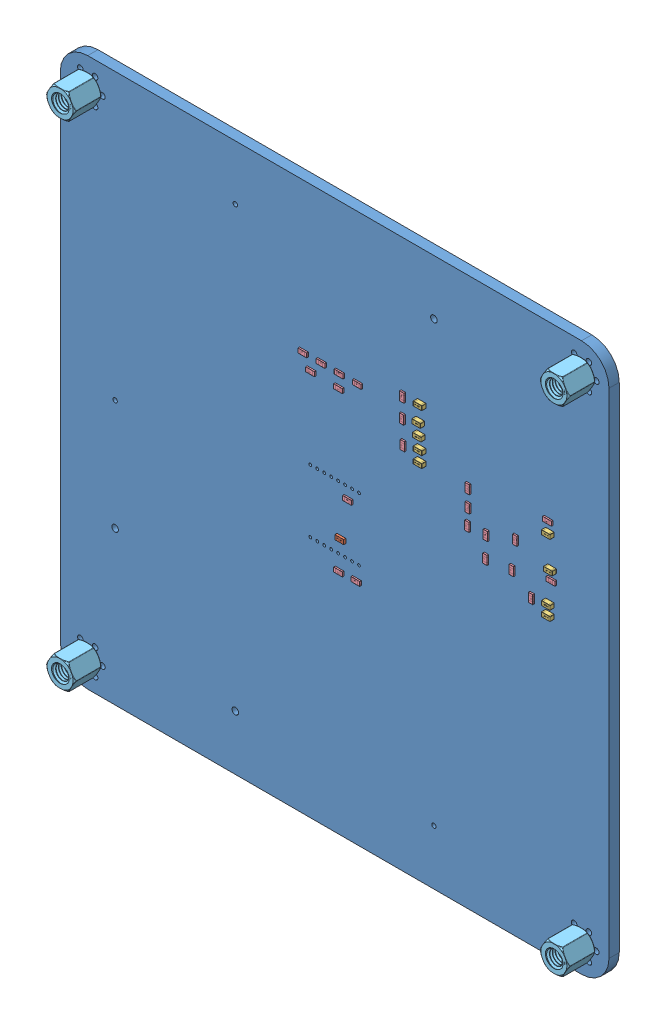
SolidWorks assembly sensor, configuration 默认. Lengths in mm.
Overall size (100 100 12.35).
156 component instances, 17 part files, 0 mates.
Components (placement in the parent):
- sensor_BOARD-1: sensor_BOARD [默认] at origin size (100 100 1.87)
- 0603R_RES-1-1: 0603R_RES-1 [默认] at (100.66 134.239 0.0102) x (-1 0 0) z (0 0 -1) size (1.6 0.82 0.45)
- 0603R_RES-1-2: 0603R_RES-1 [默认] at (75.184 135.128 0.0102) x (0 -1 0) z (0 0 -1) size (1.6 0.82 0.45)
- 0603R_RES-1-3: 0603R_RES-1 [默认] at (96.901 134.239 0.0102) x (-1 0 0) z (0 0 -1) size (1.6 0.82 0.45)
- 0603R_RES-1-4: 0603R_RES-1 [默认] at (77.089 133.528 0.0102) x (0 1 0) z (0 0 -1) size (1.6 0.82 0.45)
- 0603R_RES-1-5: 0603R_RES-1 [默认] at (74.803 117.551 0.0102) x (0 -1 0) z (0 0 -1) size (1.6 0.82 0.45)
- 0603R_RES-1-6: 0603R_RES-1 [默认] at (96.52 116.84 0.0102) x (-1 0 0) z (0 0 -1) size (1.6 0.82 0.45)
- 0603R_RES-1-7: 0603R_RES-1 [默认] at (77.089 115.951 0.0102) x (0 1 0) z (0 0 -1) size (1.6 0.82 0.45)
- 0603R_RES-1-8: 0603R_RES-1 [默认] at (100.914 98.044 0.0102) x (-1 0 0) z (0 0 -1) size (1.6 0.82 0.45)
- 0603R_RES-1-9: 0603R_RES-1 [默认] at (74.549 126.314 0.0102) x (0 -1 0) z (0 0 -1) size (1.6 0.82 0.45)
- 0603R_RES-1-10: 0603R_RES-1 [默认] at (96.723 126.365 0.0102) x (-1 0 0) z (0 0 -1) size (1.6 0.82 0.45)
- 0603R_RES-1-11: 0603R_RES-1 [默认] at (76.835 124.841 0.0102) x (0 1 0) z (0 0 -1) size (1.6 0.82 0.45)
- 0603R_RES-1-12: 0603R_RES-1 [默认] at (108.407 105.283 0.0102) x (-1 0 0) z (0 0 -1) size (1.6 0.82 0.45)
- 0603R_RES-1-13: 0603R_RES-1 [默认] at (108.331 103.251 0.0102) x (-1 0 0) z (0 0 -1) size (1.6 0.82 0.45)
- 0603R_RES-1-14: 0603R_RES-1 [默认] at (108.204 101.092 0.0102) x (-1 0 0) z (0 0 -1) size (1.6 0.82 0.45)
- 0603R_RES-1-15: 0603R_RES-1 [默认] at (108.204 98.679 0.0102) x (-1 0 0) z (0 0 -1) size (1.6 0.82 0.45)
- 0603R_RES-1-16: 0603R_RES-1 [默认] at (100.584 126.365 0.0102) x (-1 0 0) z (0 0 -1) size (1.6 0.82 0.45)
- 0603R_RES-1-17: 0603R_RES-1 [默认] at (120.777 104.14 1.8635) x (-1 0 0) z (0 0 1) size (1.6 0.82 0.45)
- 0603R_RES-1-18: 0603R_RES-1 [默认] at (156.159 113.284 0.0102) x (-1 0 0) z (0 0 -1) size (1.6 0.82 0.45)
- 0603R_RES-1-19: 0603R_RES-1 [默认] at (147.32 139.014 0.0102) x (0 -1 0) z (0 0 -1) size (1.6 0.82 0.45)
- 0603R_RES-1-20: 0603R_RES-1 [默认] at (145.161 139.014 0.0102) x (0 -1 0) z (0 0 -1) size (1.6 0.82 0.45)
- 0603R_RES-1-21: 0603R_RES-1 [默认] at (141.097 139.014 0.0102) x (0 -1 0) z (0 0 -1) size (1.6 0.82 0.45)
- 0603R_RES-1-22: 0603R_RES-1 [默认] at (143.129 139.014 0.0102) x (0 -1 0) z (0 0 -1) size (1.6 0.82 0.45)
- 0603R_RES-1-23: 0603R_RES-1 [默认] at (80.645 73.787 0.0102) x (0 -1 0) z (0 0 -1) size (1.6 0.82 0.45)
- 0603R_RES-1-24: 0603R_RES-1 [默认] at (83.058 73.99 0.0102) x (0 -1 0) z (0 0 -1) size (1.6 0.82 0.45)
- 0603R_RES-1-25: 0603R_RES-1 [默认] at (77.978 72.263 0.0102) x (0 1 0) z (0 0 -1) size (1.6 0.82 0.45)
- 0603R_RES-1-26: 0603R_RES-1 [默认] at (97.663 66.929 0.0102) x (0 1 0) z (0 0 -1) size (1.6 0.82 0.45)
- 0603R_RES-1-27: 0603R_RES-1 [默认] at (97.536 71.501 0.0102) x (0 1 0) z (0 0 -1) size (1.6 0.82 0.45)
- 0603R_RES-1-28: 0603R_RES-1 [默认] at (78.232 75.946 0.0102) x (1 0 0) z (0 0 -1) size (1.6 0.82 0.45)
- 0603R_RES-1-29: 0603R_RES-1 [默认] at (112.522 88.951 0.0102) x (0 1 0) z (0 0 -1) size (1.6 0.82 0.45)
- 0603R_RES-1-30: 0603R_RES-1 [默认] at (112.522 87.198 0.0102) x (0 -1 0) z (0 0 -1) size (1.6 0.82 0.45)
- 0603R_RES-1-31: 0603R_RES-1 [默认] at (112.522 83.642 0.0102) x (0 -1 0) z (0 0 -1) size (1.6 0.82 0.45)
- 0603R_RES-1-32: 0603R_RES-1 [默认] at (112.522 80.264 0.0102) x (0 -1 0) z (0 0 -1) size (1.6 0.82 0.45)
- 0603R_RES-1-33: 0603R_RES-1 [默认] at (131.5085 109.144 0.0102) x (0 1 0) z (0 0 -1) size (1.6 0.82 0.45)
- 0603R_RES-1-34: 0603R_RES-1 [默认] at (102.362 139.065 0.0102) x (0 1 0) z (0 0 -1) size (1.6 0.82 0.45)
- 0603R_RES-1-35: 0603R_RES-1 [默认] at (131.953 139.7 0.0102) x (0 1 0) z (0 0 -1) size (1.6 0.82 0.45)
- 0603R_RES-1-36: 0603R_RES-1 [默认] at (129.794 139.751 0.0102) x (0 1 0) z (0 0 -1) size (1.6 0.82 0.45)
- 0603R_RES-1-37: 0603R_RES-1 [默认] at (127.635 139.7 0.0102) x (0 1 0) z (0 0 -1) size (1.6 0.82 0.45)
- 0603R_RES-1-38: 0603R_RES-1 [默认] at (118.999 153.035 0.0102) x (1 0 0) z (0 0 -1) size (1.6 0.82 0.45)
- 0603R_RES-1-39: 0603R_RES-1 [默认] at (125.73 139.7 0.0102) x (0 1 0) z (0 0 -1) size (1.6 0.82 0.45)
- 0603R_RES-1-40: 0603R_RES-1 [默认] at (123.698 139.624 0.0102) x (0 1 0) z (0 0 -1) size (1.6 0.82 0.45)
- 0603R_RES-1-41: 0603R_RES-1 [默认] at (121.793 139.573 0.0102) x (0 1 0) z (0 0 -1) size (1.6 0.82 0.45)
- 0603R_RES-1-42: 0603R_RES-1 [默认] at (119.888 139.446 0.0102) x (0 1 0) z (0 0 -1) size (1.6 0.82 0.45)
- 0603R_RES-1-43: 0603R_RES-1 [默认] at (117.551 120.396 0.0102) x (-1 0 0) z (0 0 -1) size (1.6 0.82 0.45)
- 0603R_RES-1-44: 0603R_RES-1 [默认] at (117.983 139.446 0.0102) x (0 1 0) z (0 0 -1) size (1.6 0.82 0.45)
- 0603R_RES-1-45: 0603R_RES-1 [默认] at (116.078 139.319 0.0102) x (0 1 0) z (0 0 -1) size (1.6 0.82 0.45)
- 0603R_RES-1-46: 0603R_RES-1 [默认] at (121.107 120.523 0.0102) x (-1 0 0) z (0 0 -1) size (1.6 0.82 0.45)
- 0603R_RES-1-47: 0603R_RES-1 [默认] at (114.173 139.319 0.0102) x (0 1 0) z (0 0 -1) size (1.6 0.82 0.45)
- 0603R_RES-1-48: 0603R_RES-1 [默认] at (112.268 139.319 0.0102) x (0 1 0) z (0 0 -1) size (1.6 0.82 0.45)
- 0603R_RES-1-49: 0603R_RES-1 [默认] at (125.044 120.523 0.0102) x (-1 0 0) z (0 0 -1) size (1.6 0.82 0.45)
- 0603R_RES-1-50: 0603R_RES-1 [默认] at (110.363 139.192 0.0102) x (0 1 0) z (0 0 -1) size (1.6 0.82 0.45)
- 0603R_RES-1-51: 0603R_RES-1 [默认] at (108.458 139.192 0.0102) x (0 1 0) z (0 0 -1) size (1.6 0.82 0.45)
- 0603R_RES-1-52: 0603R_RES-1 [默认] at (129.235 120.523 0.0102) x (-1 0 0) z (0 0 -1) size (1.6 0.82 0.45)
- 0603R_RES-1-53: 0603R_RES-1 [默认] at (106.426 139.065 0.0102) x (0 1 0) z (0 0 -1) size (1.6 0.82 0.45)
- 0603R_RES-1-54: 0603R_RES-1 [默认] at (104.521 139.065 0.0102) x (0 1 0) z (0 0 -1) size (1.6 0.82 0.45)
- 0603R_RES-1-55: 0603R_RES-1 [默认] at (100.203 139.192 0.0102) x (0 1 0) z (0 0 -1) size (1.6 0.82 0.45)
- 0603L_FB-1-1: 0603L_FB-1 [默认] at (135.3638 127.7023 1.8635) x (-1 0 0) z (0 0 1) size (1.61 0.81 0.81)
- 0603L_FB-1-2: 0603L_FB-1 [默认] at (129.7305 104.775 0.0102) x (-1 0 0) z (0 0 -1) size (1.61 0.81 0.81)
- 0603L_FB-1-3: 0603L_FB-1 [默认] at (159.258 118.491 1.8635) x (-1 0 0) z (0 0 1) size (1.61 0.81 0.81)
- 0603L_FB-1-4: 0603L_FB-1 [默认] at (158.877 112.903 1.8635) x (-1 0 0) z (0 0 1) size (1.61 0.81 0.81)
- 0603L_FB-1-5: 0603L_FB-1 [默认] at (158.877 124.079 1.8635) x (-1 0 0) z (0 0 1) size (1.61 0.81 0.81)
- 0603L_FB-1-6: 0603L_FB-1 [默认] at (158.877 111.125 1.8635) x (-1 0 0) z (0 0 1) size (1.61 0.81 0.81)
- 0603L_FB-1-7: 0603L_FB-1 [默认] at (135.509 123.571 1.8635) x (-1 0 0) z (0 0 1) size (1.61 0.81 0.81)
- 0603L_FB-1-8: 0603L_FB-1 [默认] at (135.509 125.603 1.8635) x (-1 0 0) z (0 0 1) size (1.61 0.81 0.81)
- 0603L_FB-1-9: 0603L_FB-1 [默认] at (135.255 129.794 1.8635) x (-1 0 0) z (0 0 1) size (1.61 0.81 0.81)
- 0603L_FB-1-10: 0603L_FB-1 [默认] at (135.509 132.715 1.8635) x (-1 0 0) z (0 0 1) size (1.61 0.81 0.81)
- 0603C_CAP-1-1: 0603C_CAP-1 [默认] at (154.7204 112.9084 1.8635) x (0 -1 0) z (0 0 1) size (1.6 0.8 0.3)
- 0603C_CAP-1-2: 0603C_CAP-1 [默认] at (122.2956 130.057 1.8635) size (1.6 0.8 0.3)
- 0603C_CAP-1-3: 0603C_CAP-1 [默认] at (131.2834 131.4396 1.8635) x (0 1 0) z (0 0 1) size (1.6 0.8 0.3)
- 0603C_CAP-1-4: 0603C_CAP-1 [默认] at (88.147 133.4716 0.0102) x (0 1 0) z (0 0 -1) size (1.6 0.8 0.3)
- 0603C_CAP-1-5: 0603C_CAP-1 [默认] at (89.925 133.4716 0.0102) x (0 1 0) z (0 0 -1) size (1.6 0.8 0.3)
- 0603C_CAP-1-6: 0603C_CAP-1 [默认] at (98.806 105.41 0.0102) x (-1 0 0) z (0 0 -1) size (1.6 0.8 0.3)
- 0603C_CAP-1-7: 0603C_CAP-1 [默认] at (98.8114 103.4124 0.0102) x (-1 0 0) z (0 0 -1) size (1.6 0.8 0.3)
- 0603C_CAP-1-8: 0603C_CAP-1 [默认] at (85.9736 99.94 0.0102) x (1 0 0) z (0 0 -1) size (1.6 0.8 0.3)
- 0603C_CAP-1-9: 0603C_CAP-1 [默认] at (87.63 116.205 0.0102) x (0 1 0) z (0 0 -1) size (1.6 0.8 0.3)
- 0603C_CAP-1-10: 0603C_CAP-1 [默认] at (89.671 116.1996 0.0102) x (0 1 0) z (0 0 -1) size (1.6 0.8 0.3)
- 0603C_CAP-1-11: 0603C_CAP-1 [默认] at (101.2244 94.0144 0.0102) x (-1 0 0) z (0 0 -1) size (1.6 0.8 0.3)
- 0603C_CAP-1-12: 0603C_CAP-1 [默认] at (89.8996 125.3436 0.0102) x (0 1 0) z (0 0 -1) size (1.6 0.8 0.3)
- 0603C_CAP-1-13: 0603C_CAP-1 [默认] at (88.02 125.3436 0.0102) x (0 1 0) z (0 0 -1) size (1.6 0.8 0.3)
- 0603C_CAP-1-14: 0603C_CAP-1 [默认] at (100.3354 116.8744 0.0102) x (-1 0 0) z (0 0 -1) size (1.6 0.8 0.3)
- 0603C_CAP-1-15: 0603C_CAP-1 [默认] at (122.0416 98.8404 1.8635) size (1.6 0.8 0.3)
- 0603C_CAP-1-16: 0603C_CAP-1 [默认] at (134.6889 110.6514 0.0102) x (-1 0 0) z (0 0 -1) size (1.6 0.8 0.3)
- 0603C_CAP-1-17: 0603C_CAP-1 [默认] at (120.4014 98.797 1.8635) x (-1 0 0) z (0 0 1) size (1.6 0.8 0.3)
- 0603C_CAP-1-18: 0603C_CAP-1 [默认] at (129.6724 106.689 0.0102) x (-1 0 0) z (0 0 -1) size (1.6 0.8 0.3)
- 0603C_CAP-1-19: 0603C_CAP-1 [默认] at (159.1364 116.704 1.8635) x (-1 0 0) z (0 0 1) size (1.6 0.8 0.3)
- 0603C_CAP-1-20: 0603C_CAP-1 [默认] at (143.12 116.9616 1.8635) x (0 1 0) z (0 0 1) size (1.6 0.8 0.3)
- 0603C_CAP-1-21: 0603C_CAP-1 [默认] at (143.1634 121.4174 1.8635) x (0 -1 0) z (0 0 1) size (1.6 0.8 0.3)
- 0603C_CAP-1-22: 0603C_CAP-1 [默认] at (143.1634 124.4654 1.8635) x (0 -1 0) z (0 0 1) size (1.6 0.8 0.3)
- 0603C_CAP-1-23: 0603C_CAP-1 [默认] at (158.5014 125.848 1.8635) x (-1 0 0) z (0 0 1) size (1.6 0.8 0.3)
- 0603C_CAP-1-24: 0603C_CAP-1 [默认] at (146.5236 117.2156 1.8635) x (0 1 0) z (0 0 1) size (1.6 0.8 0.3)
- 0603C_CAP-1-25: 0603C_CAP-1 [默认] at (146.422 113.4056 1.8635) x (0 1 0) z (0 0 1) size (1.6 0.8 0.3)
- 0603C_CAP-1-26: 0603C_CAP-1 [默认] at (151.8576 119.1206 1.8635) x (0 1 0) z (0 0 1) size (1.6 0.8 0.3)
- 0603C_CAP-1-27: 0603C_CAP-1 [默认] at (151.248 114.0406 1.8635) x (0 1 0) z (0 0 1) size (1.6 0.8 0.3)
- 0603C_CAP-1-28: 0603C_CAP-1 [默认] at (138.421 113.4164 0.0102) x (0 -1 0) z (0 0 -1) size (1.6 0.8 0.3)
- 0603C_CAP-1-29: 0603C_CAP-1 [默认] at (154.6806 118.3296 0.0102) x (1 0 0) z (0 0 -1) size (1.6 0.8 0.3)
- 0603C_CAP-1-30: 0603C_CAP-1 [默认] at (122.4334 78.5204 0.0102) x (-1 0 0) z (0 0 -1) size (1.6 0.8 0.3)
- 0603C_CAP-1-31: 0603C_CAP-1 [默认] at (129.5454 102.9044 0.0102) x (-1 0 0) z (0 0 -1) size (1.6 0.8 0.3)
- 0603C_CAP-1-32: 0603C_CAP-1 [默认] at (131.3851 123.8196 1.8635) x (0 1 0) z (0 0 1) size (1.6 0.8 0.3)
- 0603C_CAP-1-33: 0603C_CAP-1 [默认] at (115.3214 127.8546 1.8635) x (-1 0 0) z (0 0 1) size (1.6 0.8 0.3)
- 0603C_CAP-1-34: 0603C_CAP-1 [默认] at (154.6806 115.0276 0.0102) x (1 0 0) z (0 0 -1) size (1.6 0.8 0.3)
- 0603C_CAP-1-35: 0603C_CAP-1 [默认] at (120.5176 110.88 1.8635) size (1.6 0.8 0.3)
- 0603C_CAP-1-36: 0603C_CAP-1 [默认] at (154.6806 116.6786 0.0102) x (1 0 0) z (0 0 -1) size (1.6 0.8 0.3)
- 0603C_CAP-1-37: 0603C_CAP-1 [默认] at (154.6806 119.9806 0.0102) x (1 0 0) z (0 0 -1) size (1.6 0.8 0.3)
- 0603C_CAP-1-38: 0603C_CAP-1 [默认] at (154.6806 121.6316 0.0102) x (1 0 0) z (0 0 -1) size (1.6 0.8 0.3)
- 0603C_CAP-1-39: 0603C_CAP-1 [默认] at (120.4014 127.7276 1.8635) x (-1 0 0) z (0 0 1) size (1.6 0.8 0.3)
- 0603C_CAP-1-40: 0603C_CAP-1 [默认] at (131.2398 127.9509 1.8635) x (0 1 0) z (0 0 1) size (1.6 0.8 0.3)
- 0603C_CAP-1-41: 0603C_CAP-1 [默认] at (118.9936 130.057 1.8635) size (1.6 0.8 0.3)
- 0603C_CAP-1-42: 0603C_CAP-1 [默认] at (115.6916 130.0824 1.8635) size (1.6 0.8 0.3)
- 0603C_CAP-1-43: 0603C_CAP-1 [默认] at (112.3896 130.0824 1.8635) size (1.6 0.8 0.3)
- 0603C_CAP-1-44: 0603C_CAP-1 [默认] at (94.116 66.9236 0.0102) x (0 1 0) z (0 0 -1) size (1.6 0.8 0.3)
- 0603C_CAP-1-45: 0603C_CAP-1 [默认] at (85.4366 73.9194 0.0102) x (0 -1 0) z (0 0 -1) size (1.6 0.8 0.3)
- 0603C_CAP-1-46: 0603C_CAP-1 [默认] at (83.6876 70.476 0.0102) x (1 0 0) z (0 0 -1) size (1.6 0.8 0.3)
- 0603C_CAP-1-47: 0603C_CAP-1 [默认] at (100.085 71.2416 0.0102) x (0 1 0) z (0 0 -1) size (1.6 0.8 0.3)
- 0603C_CAP-1-48: 0603C_CAP-1 [默认] at (102.3964 71.2416 0.0102) x (0 1 0) z (0 0 -1) size (1.6 0.8 0.3)
- 0603C_CAP-1-49: 0603C_CAP-1 [默认] at (104.403 71.2416 0.0102) x (0 1 0) z (0 0 -1) size (1.6 0.8 0.3)
- 0603C_CAP-1-50: 0603C_CAP-1 [默认] at (89.526 90.0484 0.0102) x (0 -1 0) z (0 0 -1) size (1.6 0.8 0.3)
- 0603C_CAP-1-51: 0603C_CAP-1 [默认] at (95.0014 77.352 0.0102) x (-1 0 0) z (0 0 -1) size (1.6 0.8 0.3)
- 0603C_CAP-1-52: 0603C_CAP-1 [默认] at (114.4614 85.4656 0.0102) x (0 1 0) z (0 0 -1) size (1.6 0.8 0.3)
- 0603C_CAP-1-53: 0603C_CAP-1 [默认] at (110.5244 86.8626 0.0102) x (0 1 0) z (0 0 -1) size (1.6 0.8 0.3)
- 0603C_CAP-1-54: 0603C_CAP-1 [默认] at (128.0504 82.9256 0.0102) x (0 1 0) z (0 0 -1) size (1.6 0.8 0.3)
- 0603C_CAP-1-55: 0603C_CAP-1 [默认] at (155.448 87.757 0.0102) x (0 1 0) z (0 0 -1) size (1.6 0.8 0.3)
- 0603C_CAP-1-56: 0603C_CAP-1 [默认] at (153.552 87.7516 0.0102) x (0 1 0) z (0 0 -1) size (1.6 0.8 0.3)
- 0603C_CAP-1-57: 0603C_CAP-1 [默认] at (148.2144 80.2984 0.0102) x (-1 0 0) z (0 0 -1) size (1.6 0.8 0.3)
- 0603C_CAP-1-58: 0603C_CAP-1 [默认] at (148.2144 78.368 0.0102) x (-1 0 0) z (0 0 -1) size (1.6 0.8 0.3)
- 0603C_CAP-1-59: 0603C_CAP-1 [默认] at (114.563 78.8616 0.0102) x (0 1 0) z (0 0 -1) size (1.6 0.8 0.3)
- 0603C_CAP-1-60: 0603C_CAP-1 [默认] at (110.5244 78.7346 0.0102) x (0 1 0) z (0 0 -1) size (1.6 0.8 0.3)
- 0603C_CAP-1-61: 0603C_CAP-1 [默认] at (144.2666 109.592 0.0102) x (1 0 0) z (0 0 -1) size (1.6 0.8 0.3)
- M3x5_N_铜柱大焊盘-1-1: M3x5_N_铜柱大焊盘-1 [默认] at (163.745 62.188 1.8635) size (5.4 5.21 5.1)
- M3x5_N_铜柱大焊盘-1-2: M3x5_N_铜柱大焊盘-1 [默认] at (73.745 62.188 1.8635) size (5.4 5.21 5.1)
- M3x5_N_铜柱大焊盘-1-3: M3x5_N_铜柱大焊盘-1 [默认] at (163.745 152.188 1.8635) size (5.4 5.21 5.1)
- M3x5_N_铜柱大焊盘-1-4: M3x5_N_铜柱大焊盘-1 [默认] at (73.745 152.188 1.8635) size (5.4 5.21 5.1)
- SOT223_L_AMS1117-1-1: SOT223_L_AMS1117-1 [默认] at (148.788 86.2974 0.0102) x (-1 0 0) z (0 0 -1) size (7.13 8.13 1.7)
- SOIC-8_EL7156CSZ-T7-1-1: SOIC-8_EL7156CSZ-T7-1 [默认] at (82.677 134.925 0.0102) x (1 0 0) z (0 0 -1) size (6.01 5 1.9)
- SOIC-8_EL7156CSZ-T7-1-2: SOIC-8_EL7156CSZ-T7-1 [默认] at (82.55 117.602 0.0102) x (1 0 0) z (0 0 -1) size (6.01 5 1.9)
- SOIC-8_EL7156CSZ-T7-1-3: SOIC-8_EL7156CSZ-T7-1 [默认] at (82.69 126.238 0.0102) x (1 0 0) z (0 0 -1) size (6.01 5 1.9)
- TAJ-A_3216_TCAP-1-1: TAJ-A_3216_TCAP-1 [默认] at (92.202 132.668 0.0102) x (0 1 0) z (0 0 -1) size (5.92 2.74 0)
- TAJ-A_3216_TCAP-1-2: TAJ-A_3216_TCAP-1 [默认] at (92.075 115.396 0.0102) x (0 1 0) z (0 0 -1) size (5.92 2.74 0)
- TAJ-A_3216_TCAP-1-3: TAJ-A_3216_TCAP-1 [默认] at (96.139 94.107 0.0102) x (-1 0 0) z (0 0 -1) size (5.92 2.74 0)
- TAJ-A_3216_TCAP-1-4: TAJ-A_3216_TCAP-1 [默认] at (92.202 124.667 0.0102) x (0 1 0) z (0 0 -1) size (5.92 2.74 0)
- TAJ-A_3216_TCAP-1-5: TAJ-A_3216_TCAP-1 [默认] at (123.825 96.266 1.8635) x (-1 0 0) z (0 0 1) size (5.92 2.74 0)
- TAJ-A_3216_TCAP-1-6: TAJ-A_3216_TCAP-1 [默认] at (114.808 96.139 1.8635) size (5.92 2.74 0)
- L-SMD-0630_L-1-1: L-SMD-0630_L-1 [默认] at (94.107 84.074 0.0102) x (0 1 0) z (0 0 -1) size (6.95 6.6 3.03)
- L-SMD-0630_L-1-2: L-SMD-0630_L-1 [默认] at (128.27 89.154 0.0102) x (-1 0 0) z (0 0 -1) size (6.95 6.6 3.03)
- L-SMD-0630_L-1-3: L-SMD-0630_L-1 [默认] at (128.397 77.851 0.0102) x (-1 0 0) z (0 0 -1) size (6.95 6.6 3.03)
- SMA_DO-214AC_DIODE-1-1: SMA_DO-214AC_DIODE-1 [默认] at (91.694 98.171 0.0102) x (1 0 0) z (0 0 -1) size (4.6 2.7 2.4)
- SMA_DO-214AC_DIODE-1-2: SMA_DO-214AC_DIODE-1 [默认] at (83.693 78.105 0.0102) x (1 0 0) z (0 0 -1) size (4.6 2.7 2.4)
- SMA_DO-214AC_DIODE-1-3: SMA_DO-214AC_DIODE-1 [默认] at (121.666 89.027 0.0102) x (-1 0 0) z (0 0 -1) size (4.6 2.7 2.4)
- SMA_DO-214AC_DIODE-1-4: SMA_DO-214AC_DIODE-1 [默认] at (117.348 78.867 0.0102) x (0 1 0) z (0 0 -1) size (4.6 2.7 2.4)
- SMA_DO-214AC_DIODE-1-5: SMA_DO-214AC_DIODE-1 [默认] at (116.967 74.93 0.0102) x (1 0 0) z (0 0 -1) size (4.6 2.7 2.4)
- CXD3400N_CXD3400N-1-1: CXD3400N_CXD3400N-1 [默认] at (91.059 105.283 0.0102) x (1 0 0) z (0 0 -1) size (7.71 7.2 1.68)
- LT1945EMS_LT1945-1-1: LT1945EMS_LT1945-1 [默认] at (122.682 83.439 0.0102) x (1 0 0) z (0 0 -1) size (4.9 3 0.96)
- SOT23-3_NPN-1-1: SOT23-3_NPN-1 [默认] at (127.7035 112.141 0.0102) x (1 0 0) z (0 0 -1) size (3 2.4 1.05)
- TSSOP-56_LM98725CCMTX_NOPB-1-1: TSSOP-56_LM98725CCMTX_NOPB-1 [默认] at (148.843 125.245 0.0102) x (-1 0 0) z (0 0 -1) size (8.14 14.08 1.55)
- TSSOP-48_DS90CR218AMTDX_NOPB-1-1: TSSOP-48_DS90CR218AMTDX_NOPB-1 [默认] at (123.753 124.596 0.0102) x (0 1 0) z (0 0 -1) size (6.24 12.54 1.04)
- SMD-EC6.3X6.3X10_ECAP-1-1: SMD-EC6.3X6.3X10_ECAP-1 [默认] at (88.7408 84.9626 0.0102) x (-1 0 0) z (0 0 -1) size (7 6.6 5.4)
- SOIC-8_TPS54331DR-1-1: SOIC-8_TPS54331DR-1 [默认] at (91.44 72.263 0.0102) x (-1 0 0) z (0 0 -1) size (6.01 5 1.9)
